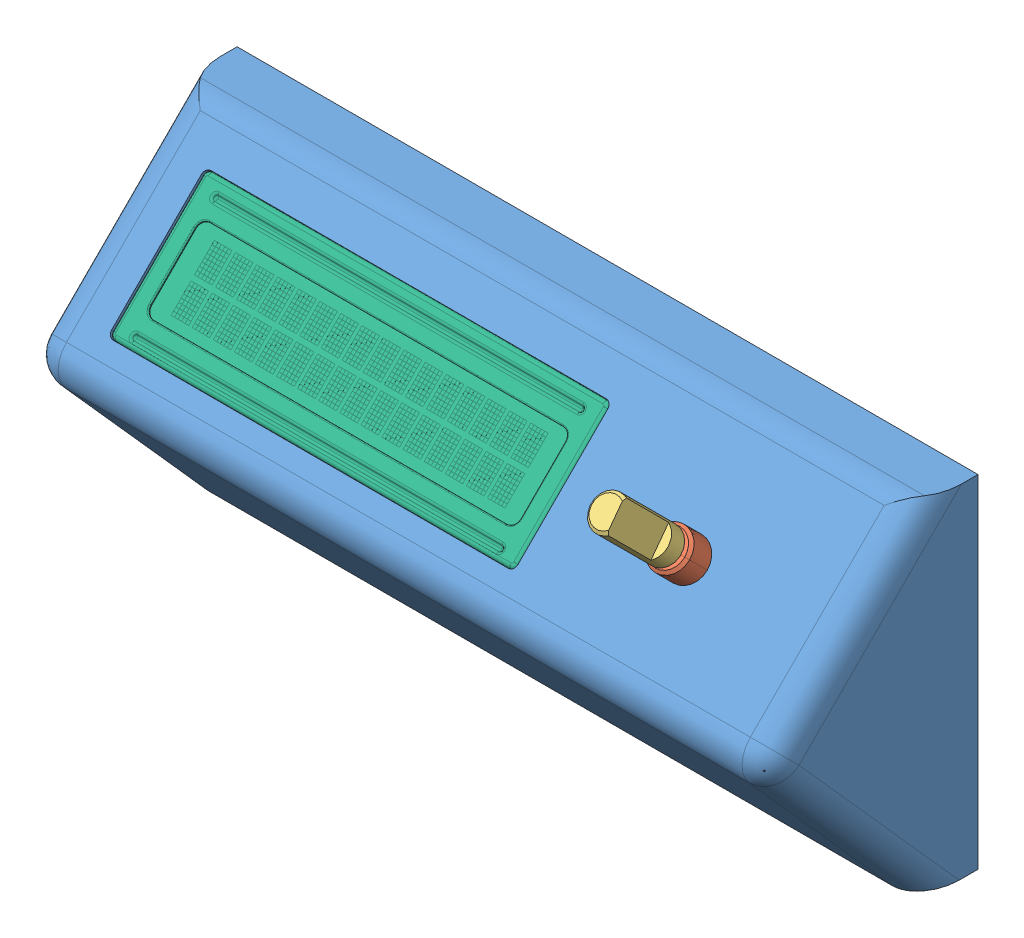
SolidWorks assembly HMI_Assembly, configuration Default. Lengths in mm.
Overall size (130 66.01 46.34).
7 component instances, 6 part files, 6 mates.
Components (placement in the parent):
- HMI-1: HMI [Default] at (46.8038 55.769 108.8963) size (130 60 36.41)
- KY-040 Rotary Encoder-1: KY-040 Rotary Encoder [Default] at (72.2658 91.6158 120.3711) x (0 0.707107 -0.707107) z (1 0 0) size (18.7 30.1 31.47)
  - Rotary Encoder-1: Rotary Encoder [Default] at (5.1929 2.265 12.688) size (11.8 14.9 15)
  - D-handle-1: D-handle [Default] at (5.1929 8.865 12.688) x (-0.994918 0 0.100689) z (-0.100689 0 -0.994918) size (6 20.2 6)
  - pcb-1: pcb [Default] at (-5.1071 1.765 2.138) x (0 0 1) z (-1 0 0) size (26.2 1.02 18.7)
  - 2.54 5PIN 90-1: 2.54 5PIN 90 [Default] at (-0.1071 2.265 26.008) x (-1 0 0) z (0 0 -1) size (12.7 7.32 8.85)
- STEP 1602 Serial LCD Module.step-1: STEP 1602 Serial LCD Module.step [Default] at (27.4538 96.3236 118.4422) x (1 0 0) z (0 -0.707107 0.707107) size (80.2 17.64 36)
Mates (geometry in assembly coordinates):
- Concentric1: concentric anti-aligned: cylinder of HMI-1 through (84.9538 30.9162 52.3277) axis (0 0.707107 0.707107) radius 3.5; cylinder of KY-040 Rotary Encoder-1/Rotary Encoder-1 through (84.9538 105.0917 126.5032) axis (0 -0.707107 -0.707107) radius 3.5
- Coincident2: coincident anti-aligned: plane of HMI-1 through (111.8038 114.3548 107.482) normal (0 -0.707107 -0.707107); plane of KY-040 Rotary Encoder-1/Rotary Encoder-1 through (84.9538 100.2127 121.6242) normal (0 0.707107 0.707107)
- Parallel1: parallel anti-aligned: plane of HMI-1 through (-16.1962 55.769 108.8963) normal (1 0 0); plane of KY-040 Rotary Encoder-1/pcb-1 through (74.4038 88.899 124.8769) normal (-1 0 0)
- Coincident4: coincident anti-aligned: plane of HMI-1 through (62.1038 22.3249 60.9191) normal (0 0.707107 -0.707107); plane of STEP 1602 Serial LCD Module.step-1 through (-8.1962 34.8215 73.4156) normal (0 -0.707107 0.707107)
- Coincident5: coincident anti-aligned: plane of HMI-1 through (-8.1962 23.032 60.212) normal (1 0 0); plane of STEP 1602 Serial LCD Module.step-1 through (-8.1962 34.8215 73.4156) normal (-1 0 0)
- Coincident6: coincident aligned: plane of HMI-1 through (111.8038 115.769 108.8963) normal (0 0.707107 0.707107); plane of STEP 1602 Serial LCD Module.step-1 through (27.4538 101.2734 123.3919) normal (0 0.707107 0.707107)
